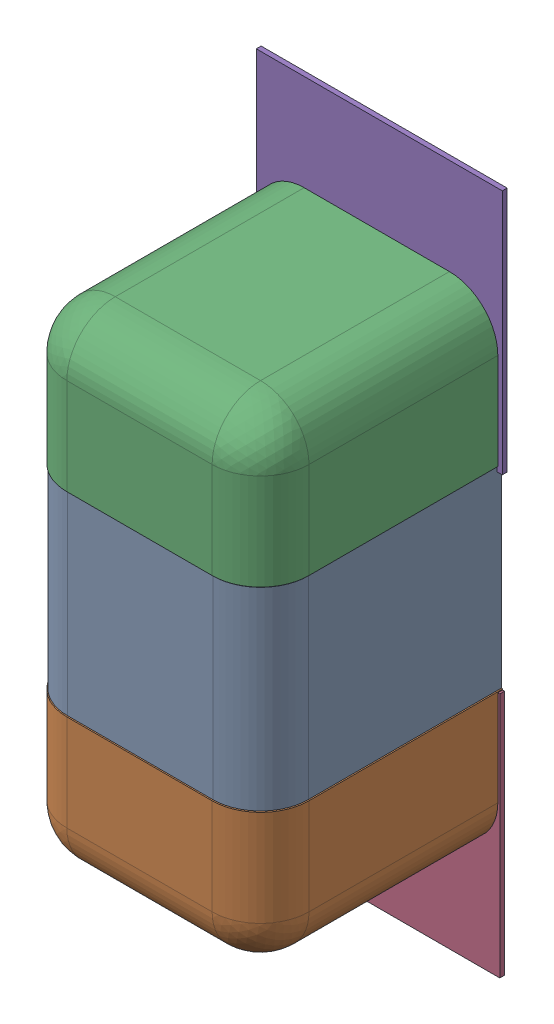
SolidWorks assembly C74, configuration Défaut. Lengths in mm.
Overall size (0.51 1.41 0.5).
8 component instances, 4 part files, 0 mates.
Components (placement in the parent):
- 6501216624-1: 6501216624 [Défaut] at (21.6154 -22.5806 0) x (0 1 0) z (1 0 0) size (1 0.5 0.5)
  - Open CASCADE STEP translator 7.5 2.111.1.1-1: Open CASCADE STEP translator 7.5 2.111.1.1 [Défaut] at origin size (0.4 0.5 0.5)
  - Open CASCADE STEP translator 7.5 2.111.1.2-1: Open CASCADE STEP translator 7.5 2.111.1.2 [Défaut] at origin size (0.3 0.5 0.5)
  - Open CASCADE STEP translator 7.5 2.111.1.3-1: Open CASCADE STEP translator 7.5 2.111.1.3 [Défaut] at origin size (0.3 0.5 0.5)
- 6504207776-1: 6504207776 [Défaut] at (21.6154 -23.0379 0) size (0.51 0.51 0.01)
  - Extruded-1: Extruded [Défaut] at origin size (0.51 0.51 0.01)
- 6504207776-2: 6504207776 [Défaut] at (21.6206 -22.1356 0) size (0.51 0.51 0.01)
  - Extruded-1: Extruded [Défaut] at origin size (0.51 0.51 0.01)
